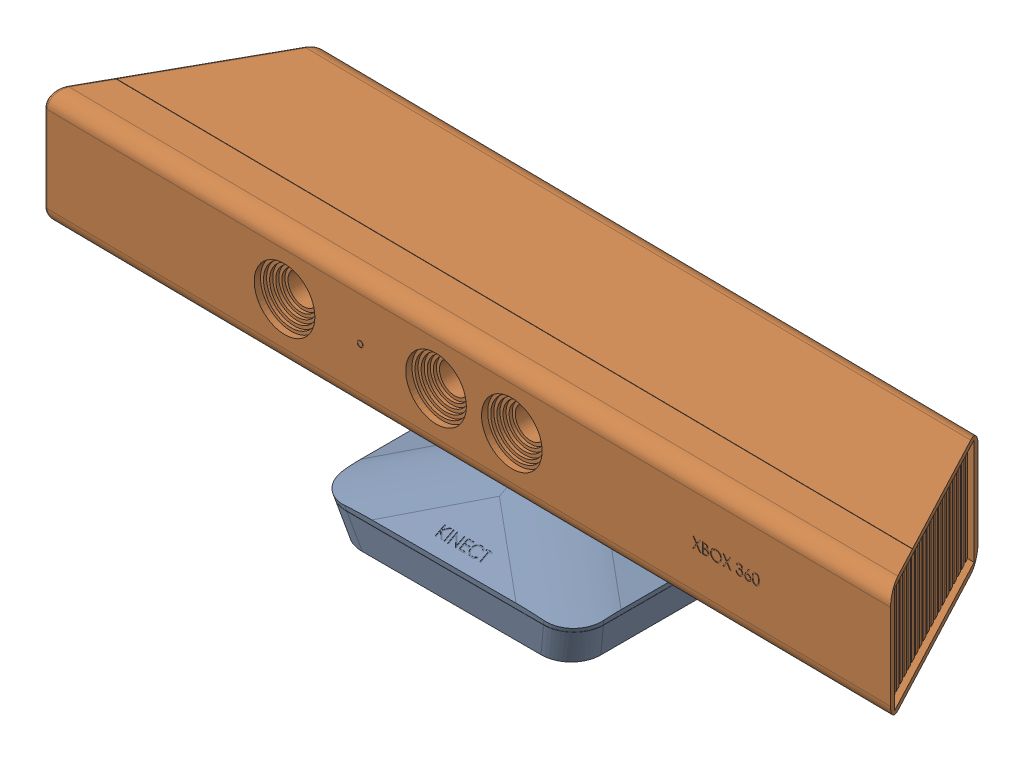
SolidWorks assembly final kinect, configuration Default. Lengths in mm.
Overall size (279.97 72.5 71.02).
2 component instances, 2 part files, 2 mates.
Components (placement in the parent):
- lower part-1: lower part [Default] at (2.1296 -16.1755 0.9636) size (86.05 27.21 71.02)
- kinect upper part-1: kinect upper part [Default] at (2.2956 17.8245 -1.5066) x (0.999938 0 0.011149) z (-0.011149 0 0.999938) size (279.32 60 60)
Mates (geometry in assembly coordinates):
- Concentric1: concentric: sphere of lower part-1; sphere of kinect upper part-1
- Parallel1: parallel anti-aligned: plane of lower part-1 through (-26.5143 -16.6755 23.2804) normal (0 -1 0); plane of kinect upper part-1 through (2.2956 55.8245 -1.5066) normal (0 1 0)
